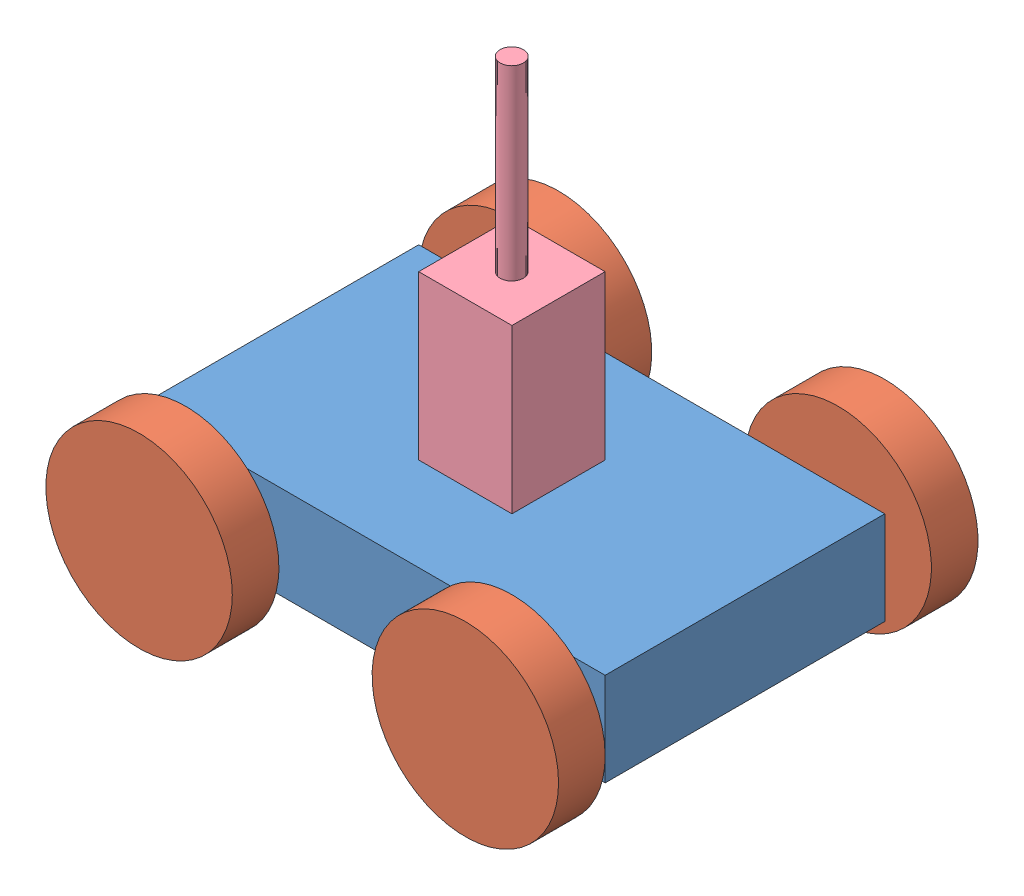
SolidWorks assembly Assignment 5 Assembly, configuration Default. Lengths in mm.
Overall size (146.23 138.37 114.3).
10 component instances, 4 part files, 11 mates.
Components (placement in the parent):
- Chassis-1: Chassis [Default] at (-66.5716 -6.2376 -61.9199) size (127 25.4 76.2)
- Wheel-1: Wheel [Default] at (-47.5216 6.4624 33.3301) x (0.998099 -0.061624 0) z (0 0 -1) size (50.8 50.8 12.7)
- Axle-1: Axle [Default] at (-47.5216 6.4624 1.5801) size (6.35 6.35 25.4)
- Wheel-2: Wheel [Default] at (41.3784 6.4624 33.3301) x (0.222543 -0.974923 0) z (0 0 -1) size (50.8 50.8 12.7)
- Wheel-3: Wheel [Default] at (41.3784 6.4624 -80.9699) size (50.8 50.8 12.7)
- Wheel-4: Wheel [Default] at (-47.5216 6.4624 -80.9699) size (50.8 50.8 12.7)
- Axle-2: Axle [Default] at (41.3784 6.4624 -74.6199) size (6.35 6.35 25.4)
- Axle-3: Axle [Default] at (41.3784 6.4624 26.9801) x (-0.967266 -0.253764 0) z (0 0 -1) size (6.35 6.35 25.4)
- Axle-4: Axle [Default] at (-47.5216 6.4624 -74.6199) size (6.35 6.35 25.4)
- Top Part Thing-1: Top Part Thing [Default] at (-15.7716 12.8124 -11.1199) size (25.4 101.6 25.4)
Mates (geometry in assembly coordinates):
- Coincident3: coincident anti-aligned: circle of Wheel-1; circle of Axle-1
- Coincident5: coincident aligned: circle of Chassis-1; circle of Axle-1
- Coincident7: coincident aligned: circle of Wheel-3; circle of Axle-2
- Coincident8: coincident aligned: circle of Wheel-2; circle of Axle-3
- Coincident9: coincident aligned: circle of Wheel-4; circle of Axle-4
- Coincident12: coincident anti-aligned: circle of Chassis-1; circle of Axle-3
- Coincident13: coincident anti-aligned: circle of Chassis-1; circle of Axle-4
- Coincident15: coincident anti-aligned: circle of Chassis-1; circle of Axle-2
- Coincident18: coincident: point of assembly; point of assembly; moEndPointRef_w of Chassis-1; moEndPointRef_w of Top Part Thing-1
- Coincident21: coincident: line of Chassis-1 through (9.6284 12.8124 -11.1199) axis (0 0 -1); line of Top Part Thing-1 through (9.6284 12.8124 -11.1199) axis (0 0 -1)
- Coincident22: coincident anti-aligned: plane of Chassis-1 through (9.6284 12.8124 -36.5199) normal (-1 0 0); plane of Top Part Thing-1 through (9.6284 63.6124 -11.1199) normal (1 0 0)
